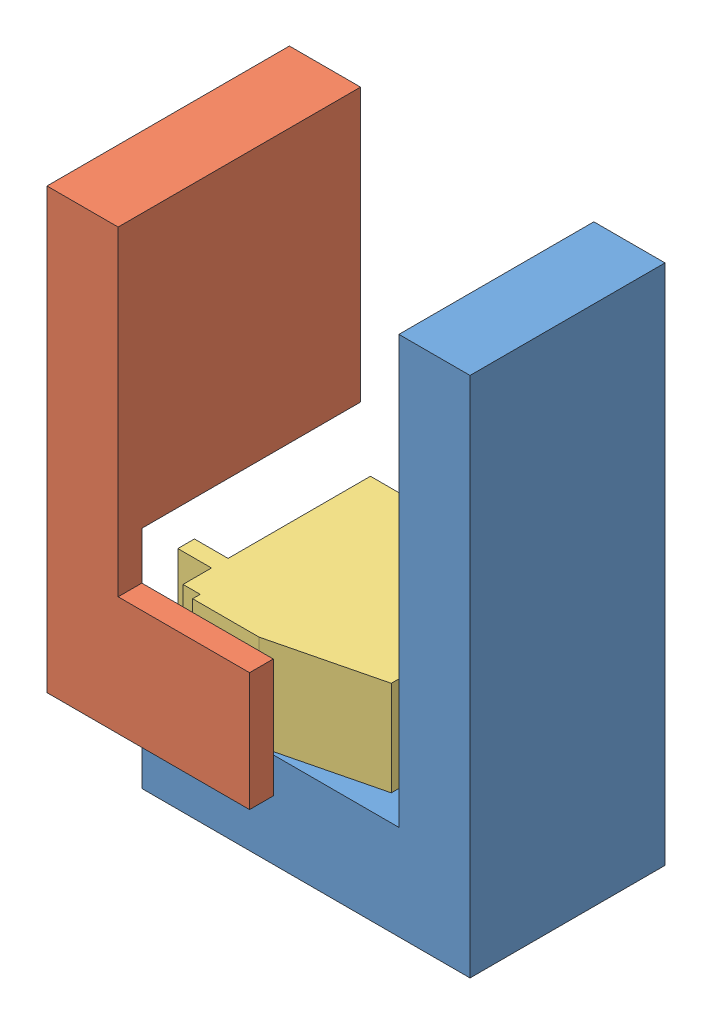
SolidWorks assembly EE-Assembly-01, configuration Default. Lengths in mm.
Overall size (79.18 110 51.1).
5 component instances, 4 part files, 5 mates.
Components (placement in the parent):
- EE-Part-1-1: EE-Part-1 [Default] at (45.9054 13.4136 84.1919) size (69.2 110 41.1)
- EE-Part-2-1: EE-Part-2 [Default] at (69.0263 43.4136 127.0919) x (-1 0 0) z (0 -1 0) size (42.7 51.1 92.5)
- Servo-02-1: Servo-02 [Default] at (7.2763 51.7068 44.0704) x (0 -1 0) z (0 0 1) size (20.01 54.2 48.1)
  - Servo-Body-6mm-1: Servo-Body-6mm [Default] at (8.2932 21.7501 21.9215) size (20.01 54.2 48.1)
  - Servo-Horn-1: Servo-Horn [Default] at (8.2932 21.7501 68.0215) size (20 20 5.5)
Mates (geometry in assembly coordinates):
- Coincident1: coincident anti-aligned: plane of EE-Part-1-1 through (45.9054 33.4136 84.1919) normal (0 1 0); plane of Servo-02-1/Servo-Body-6mm-1 through (29.0263 33.4136 65.9919) normal (0 -1 0)
- Coincident3: coincident aligned: plane of EE-Part-1-1 through (11.3054 23.4136 107.0919) normal (0 0 1); plane of Servo-02-1/Servo-Body-6mm-1 through (36.0263 53.4136 107.0919) normal (0 0 1)
- Coincident4: coincident anti-aligned: plane of EE-Part-1-1 through (65.5054 133.4136 107.0919) normal (-1 0 0); plane of Servo-02-1/Servo-Body-6mm-1 through (65.5054 61.3275 95.9919) normal (1 0 0)
- Coincident5: coincident anti-aligned: plane of EE-Part-2-1 through (29.0263 43.4136 114.0919) normal (0 0 -1); plane of Servo-02-1/Servo-Horn-1 through (29.0263 43.4136 114.0919) normal (0 0 1)
- Concentric1: concentric aligned: cylinder of EE-Part-2-1 through (29.0263 43.4136 114.0919) axis (0 0 -1) radius 10; cylinder of Servo-02-1/Servo-Horn-1 through (29.0263 43.4136 114.0919) axis (0 0 -1) radius 10
